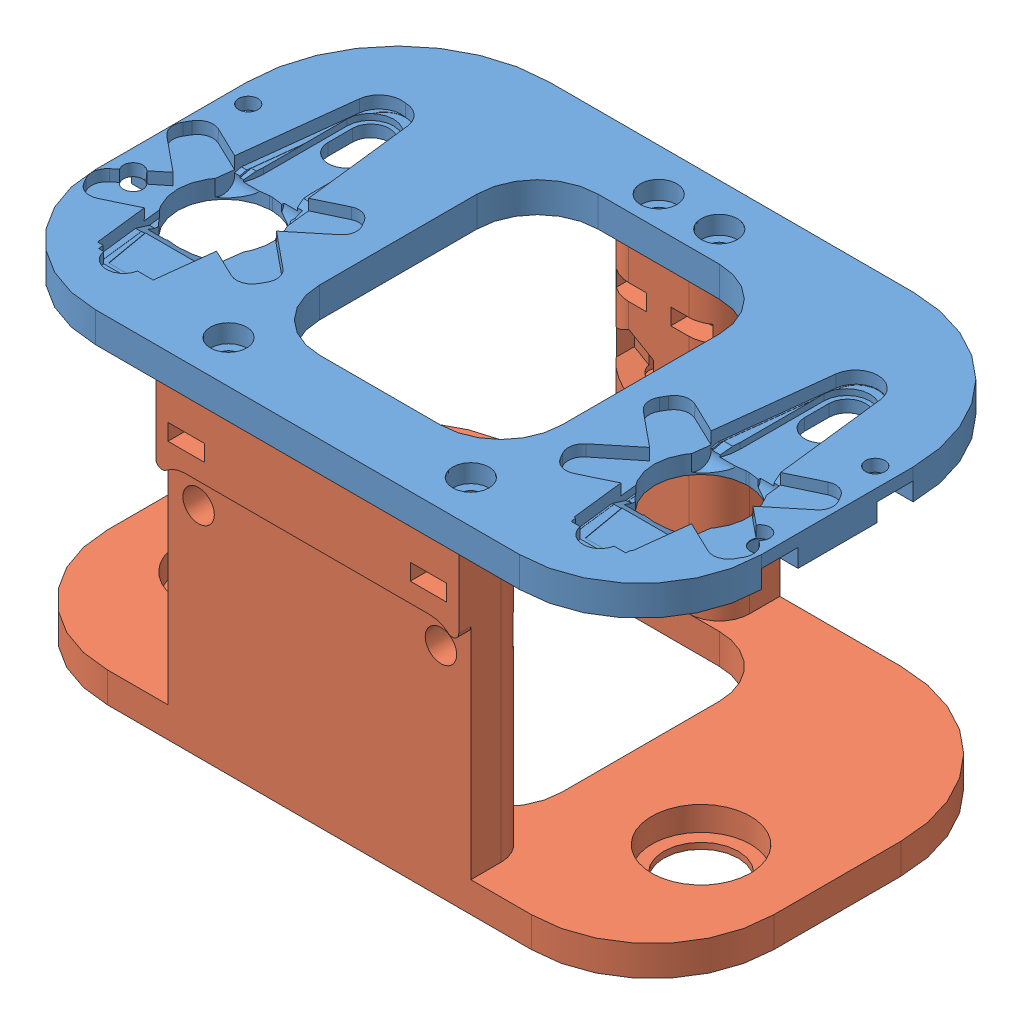
SolidWorks assembly Rear_Shoulder, configuration Default. Lengths in mm.
Overall size (110 57.5 70).
2 component instances, 2 part files, 0 mates.
Components (placement in the parent):
- Rear_Inner_Shoulder-1: Rear_Inner_Shoulder [Default] at (267.0968 85.9341 878.7869) x (-1 0 0) z (0 0 -1) size (110 5.15 70)
- Rear_Outer_Shoulder-1: Rear_Outer_Shoulder [Default] at (267.0969 90.6943 -58.2152) x (-1 0 0) z (0 0 1) size (110 52.53 70)
